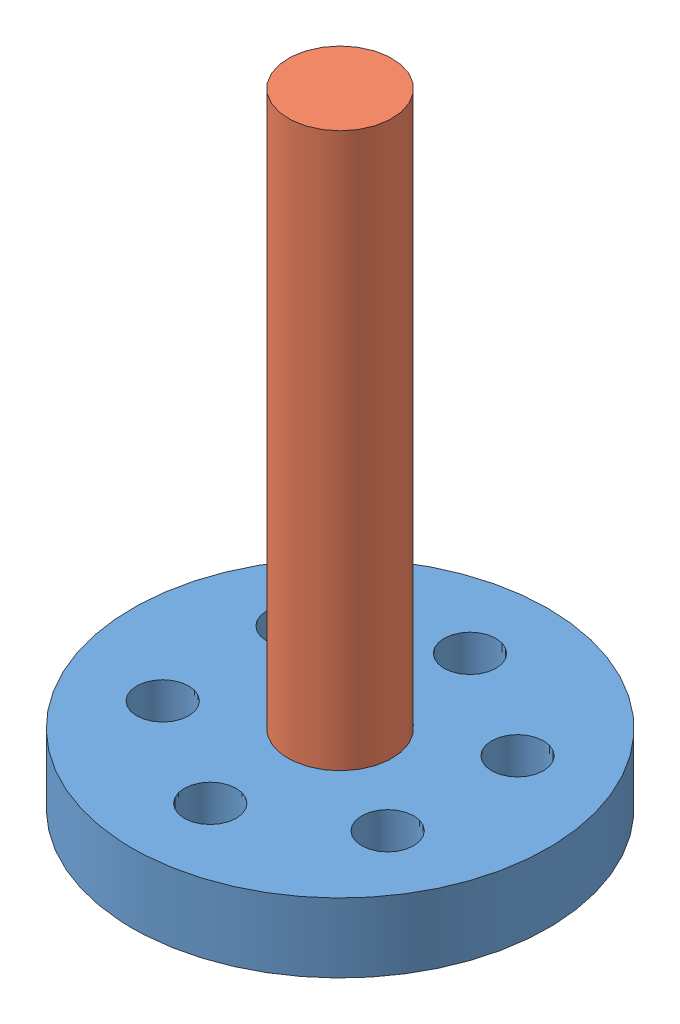
SolidWorks assembly Assem2, configuration Default. Lengths in mm.
Overall size (25.4 38.1 25.4).
2 component instances, 2 part files, 2 mates.
Components (placement in the parent):
- disk futureversion-1: disk futureversion [Default] at (9.6878 13.145 19.4624) size (25.4 4.23 25.4)
- peg futureversion-1: peg futureversion [Default] at (9.6878 30.0784 19.4624) x (0.18203 0 0.983293) z (-0.983293 0 0.18203) size (6.35 38.1 6.35)
Mates (geometry in assembly coordinates):
- Coincident1: coincident aligned: plane of disk futureversion-1 through (9.6878 11.0284 19.4624) normal (0 -1 0); plane of peg futureversion-1 through (9.6878 11.0284 19.4624) normal (0 -1 0)
- Concentric1: concentric aligned: cylinder of disk futureversion-1 through (9.6878 15.2617 19.4624) axis (0 -1 0) radius 3.175; cylinder of peg futureversion-1 through (9.6878 49.1284 19.4624) axis (0 -1 0) radius 3.175
